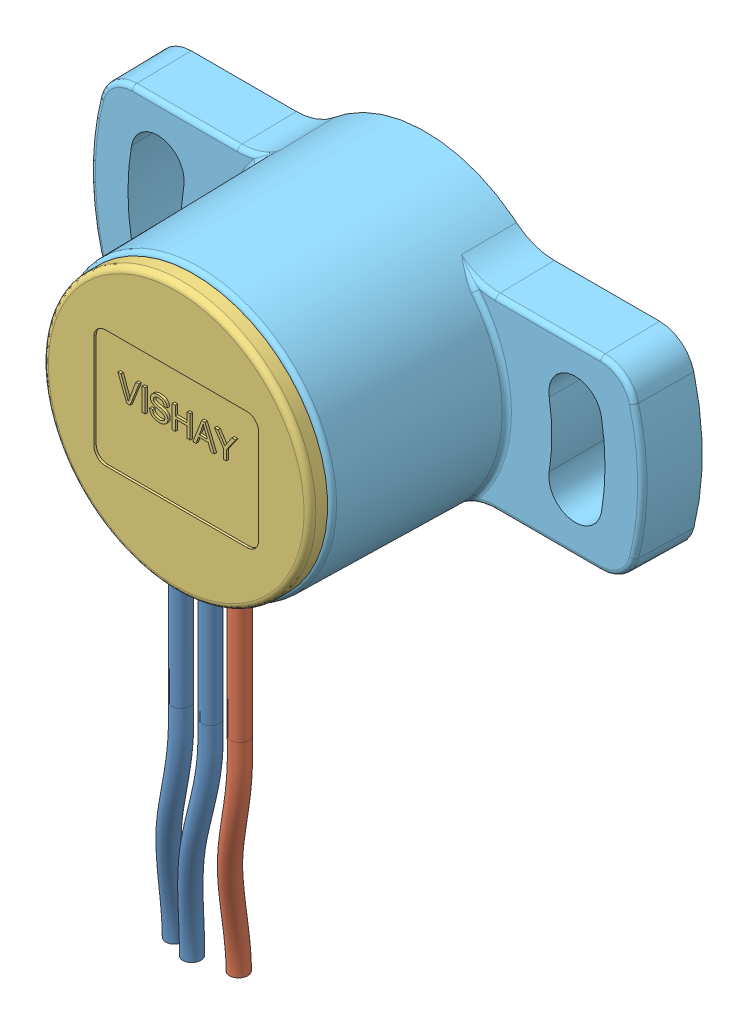
SolidWorks assembly APPS New Sensor 981HE-0-W-A-8H01_-, configuration Default. Lengths in mm.
Overall size (47 54.03 24.15).
7 component instances, 5 part files, 0 mates.
Components (placement in the parent):
- 981HE-0-W-A-8H01_-.stp-1: 981HE-0-W-A-8H01_-.stp [Default] at origin size (47 54.03 24.15)
  - fil.stp-1: fil.stp [Default] at (0.0659 -16.8453 17.8555) x (0 1 0) z (-0.164812 0 0.986325) size (44.03 5.15 2.86)
  - fil-oa0.stp-1: fil-oa0.stp [Default] at (2.6718 -16.8453 17.8888) x (0 1 0) z (-0.429519 0 0.903058) size (44.03 5.15 2.86)
  - fil.stp-2: fil.stp [Default] at (-2.3575 -16.8453 17.8762) x (0 1 0) z (-0.356185 0 0.934415) size (44.03 5.15 2.86)
  - cc00273_-.stp-1: cc00273_-.stp [Default] at (0 0 18.15) x (0 0 1) z (-1 0 0) size (3.78 22.7 22.7)
  - cn00253.stp-1: cn00253.stp [Default] at (0 0 -1.4) x (-1 0 0) z (0 0 -1) size (17.7 17.7 14)
  - CB00527b.stp-1: CB00527b.stp [Default] at origin size (47 24 22.61)
